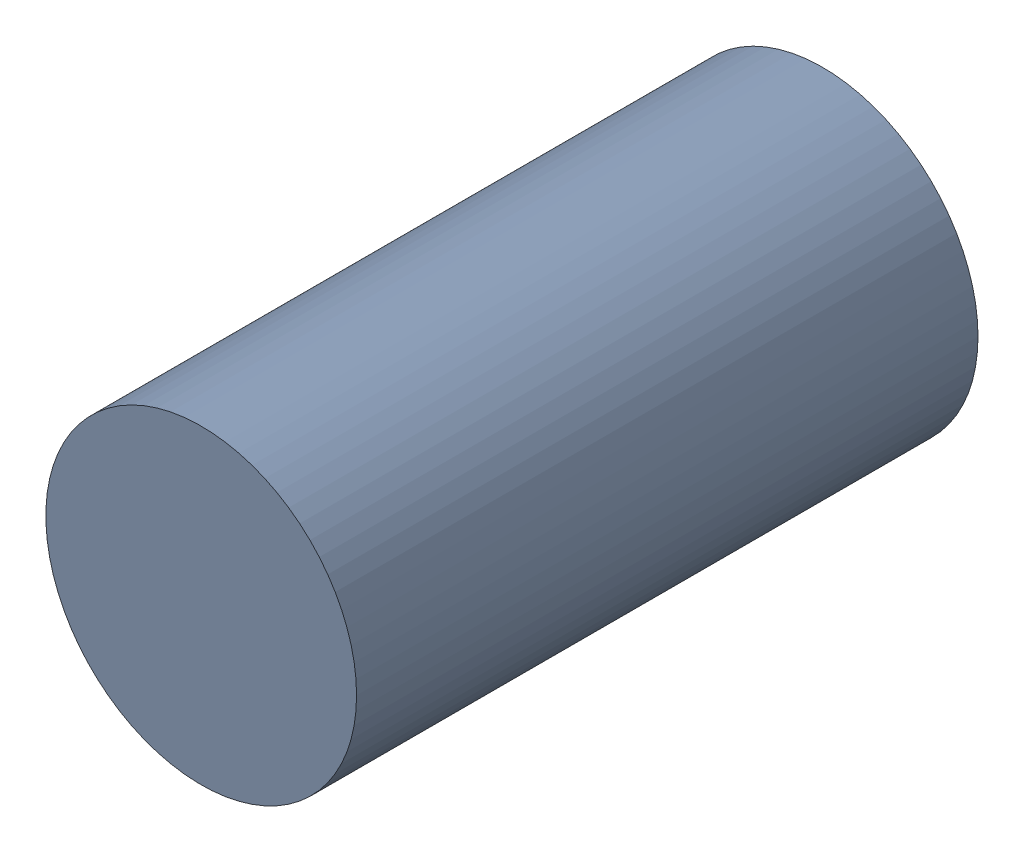
SolidWorks assembly MH5_1.step, configuration Default. Lengths in mm.
Overall size (1 1 2).
2 component instances, 1 part files, 0 mates.
Components (placement in the parent):
- 9228463120_1.step-3: 9228463120_1.step [Default] at (487.68 316.992 -1.5) size (1 1 2)
  - Cylinder_1.step-26: Cylinder_1.step [Default] at origin size (1 1 2)
